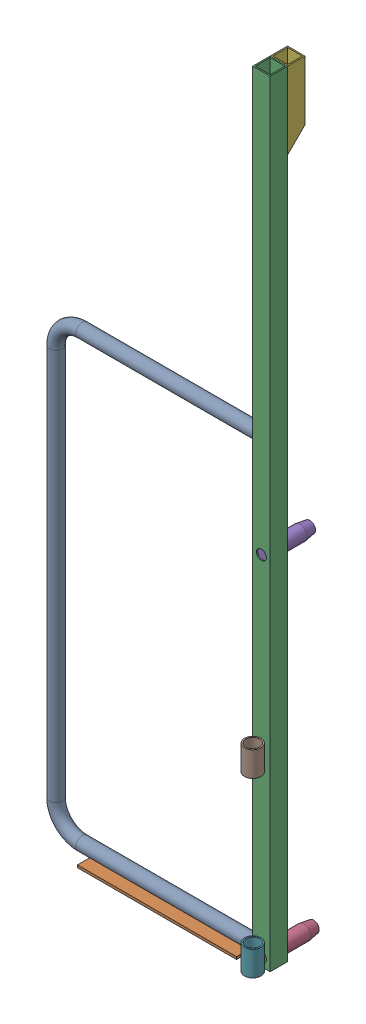
SolidWorks assembly FE-00002-12_, configuration Default. Lengths in mm.
Overall size (585.85 1981.2 175.51).
8 component instances, 7 part files, 0 mates.
Components (placement in the parent):
- FE-00002-06_-1: FE-00002-06_ [Default] at (-1178.8341 0 28.1228) x (-1 0 0) z (0 0 -1) size (541.4 1168.46 33.4)
- FE-00002-07_-1: FE-00002-07_ [Default] at (-666.3298 -164.7728 9.4541) x (-1 0 0) z (0 -1 0) size (406.4 76.2 6.35)
- FE-00002-05_-1: FE-00002-05_ [Default] at (-583.6523 -171.1228 37.2156) x (0 0 1) z (0 1 0) size (44.45 44.45 1981.2)
- FE-00002-01_-1: FE-00002-01_ [Default] at (-578.558 -161.4938 -83.0022) size (36.51 36.51 130.18)
- FE-00002-02_-1: FE-00002-02_ [Default] at (-578.558 727.5062 -73.4772) size (36.51 36.51 120.65)
- FE-00002-03_-1: FE-00002-03_ [Default] at (-575.0225 1613.2272 -11.8343) x (1 0 0) z (0 1 0) size (44.45 44.45 196.85)
- FE-00002-9_REV2_-1: FE-00002-9_REV2_ [Default] at (-584.5397 -171.1228 71.4298) size (42.16 63.5 42.16)
- FE-00002-9_REV2_-2: FE-00002-9_REV2_ [Default] at (-584.5397 270.2022 71.4298) size (42.16 63.5 42.16)
